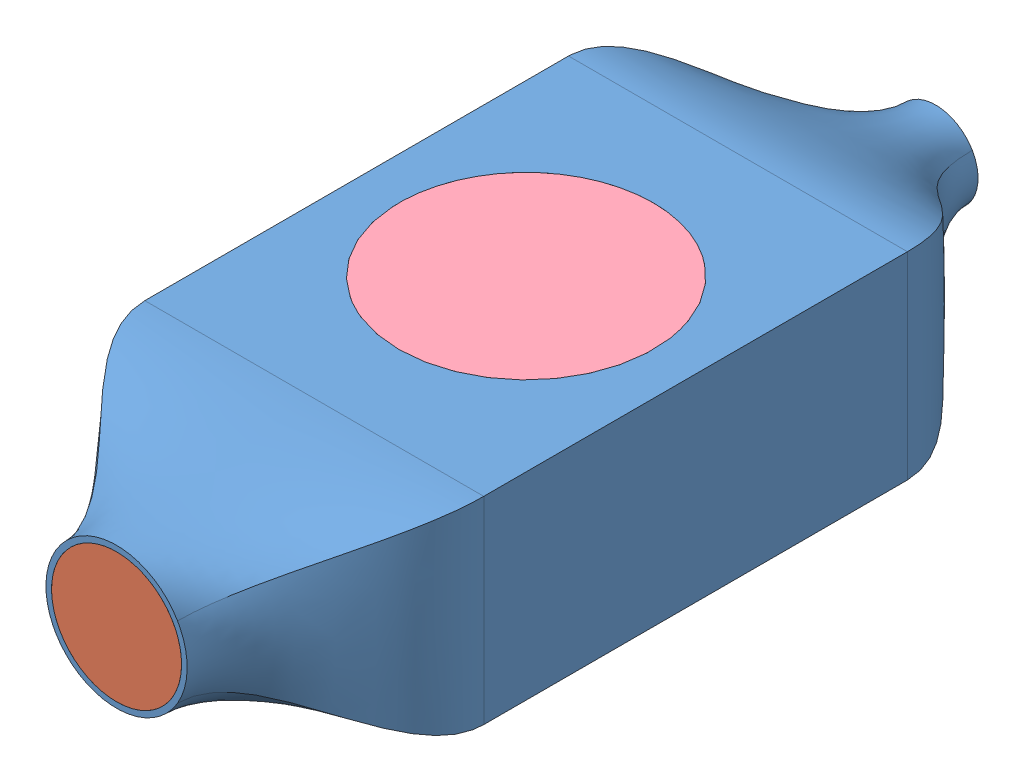
SolidWorks assembly FlowAnalysisPipeAssembly, configuration Default. Lengths in mm.
Overall size (129.55 79.55 290.01).
5 component instances, 4 part files, 8 mates.
Components (placement in the parent):
- Pipe-1: Pipe [Default] at origin size (129.55 79.55 290.01)
- inletLid-1: inletLid [Default] x (0.923728 0.383049 0) z (0 0 -1) size (46 46 2)
- outletLid-1: outletLid [Default] at (0 0 -288) x (0.923728 0.383049 0) z (0 0 -1) size (26 26 2)
- LidTop-1: LidTop [Default] at (0 33 -145) size (90 2 90)
- LidTop-2: LidTop [Default] at (0 -35 -145) size (90 2 90)
Mates (geometry in assembly coordinates):
- Concentric1: concentric aligned: circle of Pipe-1; cylinder of Pipe-1 through (0 0 2) axis (0 0 -1) radius 23
- Coincident2: coincident aligned: plane of Pipe-1 through (0 0 0) normal (0 0 1); plane of inletLid-1 through (0 0 0) normal (0 0 1)
- Coincident3: coincident aligned: plane of Pipe-1 through (0 0 -290) normal (0 0 -1); plane of outletLid-1 through (0 0 -290) normal (0 0 -1)
- Concentric2: concentric: circle of Pipe-1; cylinder of outletLid-1 through (0 0 -290) axis (0 0 -1) radius 13
- Coincident5: coincident: plane of Pipe-1 through (60 35 -358.9244) normal (0 1 0); plane of LidTop-1 through (-114.1658 35 -117.6105) normal (0 1 0)
- Concentric3: concentric: cylinder of Pipe-1 through (0 -162.2792 -145) axis (0 1 0) radius 45; cylinder of LidTop-1 through (0 35 -145) axis (0 -1 0) radius 45
- Coincident6: coincident: plane of Pipe-1 through (60 -35 -358.9244) normal (0 -1 0); plane of LidTop-2 through (-96.1211 -35 -155.3148) normal (0 -1 0)
- Concentric4: concentric: cylinder of Pipe-1 through (0 -162.2792 -145) axis (0 1 0) radius 45; circle of LidTop-2
